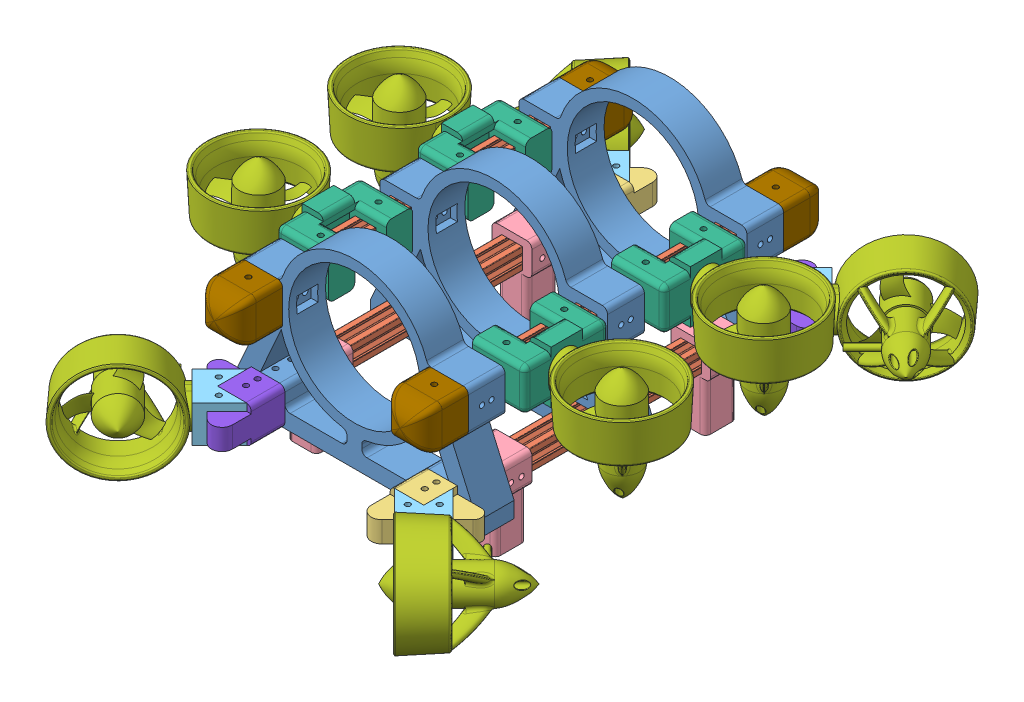
SolidWorks assembly aracson, configuration Varsayılan. Lengths in mm.
Overall size (470.39 214.66 570.15).
37 component instances, 10 part files, 72 mates.
Components (placement in the parent):
- tup30cmbirlesik-1: tup30cmbirlesik [Varsayılan] at (-12.712 13.1831 -30.3728) size (234 173.21 358.25)
  - auv_on-1: auv_on [Varsayılan] at (-0.4985 6.4776 216.5) size (234 172.66 35)
  - auvtup30cm-1: auvtup30cm [Default] at (13.0956 8.6338 230.5) x (0.999767 -0.021578 0) z (0 0 1) size (143.05 134.03 358.25) (hidden)
  - auv_on-2: auv_on [Varsayılan] at (-0.4985 6.4776 349) size (234 172.66 35)
  - auv_on-3: auv_on [Varsayılan] at (-0.4985 6.4776 481.5) size (234 172.66 35)
- sigma_20x20x1000-1: sigma_20x20x1000 [Varsayılan] at (71.7895 -62.5006 161.1272) x (0 0 1) z (-1 0 0) size (350 20 20)
- sigma_20x20x1000-2: sigma_20x20x1000 [Varsayılan] at (75.1683 19.479 161.1272) x (0 0 1) z (-1 0 0) size (350 20 20)
- sigma_20x20x1000-3: sigma_20x20x1000 [Varsayılan] at (-98.3505 -62.5006 161.1272) x (0 0 1) z (-1 0 0) size (350 20 20)
- sigma_20x20x1000-4: sigma_20x20x1000 [Varsayılan] at (-101.5893 19.479 161.1272) x (0 0 1) z (-1 0 0) size (350 20 20)
- motortutucuon - Copy (2)-1: motortutucuon - Copy (2) [Varsayılan] at (77.9913 -52.5006 504.2544) x (-1 0 0) z (0 -1 0) size (62.69 59.86 35)
- motortutucuon - Copy (2)-2: motortutucuon - Copy (2) [Varsayılan] at (-104.5523 -52.5006 168) x (1 0 0) z (0 -1 0) size (62.69 59.86 35)
- ayak-1: ayak [Varsayılan] at (-108.3505 -72.5006 421.1272) size (38 77 30)
- ayak-2: ayak [Varsayılan] at (-108.3505 -72.5006 221.1272) size (38 77 30)
- ayak-3: ayak [Varsayılan] at (61.7895 -72.5006 221.1272) size (38 77 30)
- ayak-4: ayak [Varsayılan] at (61.7895 -72.5006 421.1272) size (38 77 30)
- motortutucuarka-1: motortutucuarka [Varsayılan] at (107.3992 -77.5006 512.737) x (-0.707107 0 0.707107) z (-0.707107 0 -0.707107) size (39.6 35 36.98)
- motortutucuarka-2: motortutucuarka [Varsayılan] at (-105.9602 -77.5006 540.73) x (-0.707107 0 -0.707107) z (0.707107 0 -0.707107) size (39.6 35 36.98)
- motortutucuarka-3: motortutucuarka [Varsayılan] at (-133.9602 -77.5006 159.5175) x (0.707107 0 -0.707107) z (0.707107 0 0.707107) size (39.6 35 36.98)
- motortutucuarka-4: motortutucuarka [Varsayılan] at (79.3992 -77.5006 131.5245) x (0.707107 0 0.707107) z (-0.707107 0 0.707107) size (39.6 35 36.98)
- motorusttutucu-1: motorusttutucu [Varsayılan] at (55.1683 -0.521 362.3772) size (50 50 80)
- motorusttutucu-2: motorusttutucu [Varsayılan] at (55.1683 -0.521 229.8772) size (50 50 80)
- motorusttutucu-3: motorusttutucu [Varsayılan] at (-81.5893 39.479 229.8772) x (-1 0 0) z (0 0 1) size (50 50 80)
- motorusttutucu-4: motorusttutucu [Varsayılan] at (-81.5893 39.479 362.3772) x (-1 0 0) z (0 0 1) size (50 50 80)
- g350-ts-9: g350-ts [Default] at (104.9683 19.0095 404.8798) x (0 0.999962 0.008727) z (-1 0 0) size (107.98 96.84 103.47)
- g350-ts-10: g350-ts [Default] at (104.9683 19.4058 269.9346) x (0 0.999962 0.008727) z (-1 0 0) size (107.98 96.84 103.47)
- g350-ts-11: g350-ts [Default] at (-131.3893 18.7895 404.1961) x (0 0.999962 -0.008727) z (1 0 0) size (107.98 96.84 103.47)
- g350-ts-12: g350-ts [Default] at (-131.3893 20.0575 270.1899) x (0 0.999962 -0.008727) z (1 0 0) size (107.98 96.84 103.47)
- g350-ts-13: g350-ts [Default] at (92.9686 -63.0361 526.8847) x (-0.707107 0 0.707107) z (-0.707107 0 -0.707107) size (107.98 96.84 103.47)
- g350-ts-16: g350-ts [Default] at (-119.884 -61.7811 526.5234) x (0.707093 -0.006198 0.707093) z (0.707107 0 -0.707107) size (107.98 96.84 103.47)
- g350-ts-17: g350-ts [Default] at (93.3561 -66.3319 145.7642) x (-0.70708 0.008727 -0.70708) z (-0.707107 0 0.707107) size (107.98 96.84 103.47)
- g350-ts-18: g350-ts [Default] at (-119.9397 -63.3274 145.7798) x (0.707107 0 -0.707107) z (0.707107 0 0.707107) size (107.98 96.84 103.47)
- motortutucuon-1: motortutucuon [Varsayılan] at (-104.5523 -72.5006 504.2544) x (1 0 0) z (0 1 0) size (62.69 59.86 35)
- motortutucuon-2: motortutucuon [Varsayılan] at (77.9913 -72.5006 168) x (-1 0 0) z (0 1 0) size (62.69 59.86 35)
- kapak-1: kapak [Varsayılan] at (-111.5893 9.479 486.1272) size (40 40 45)
- kapak-2: kapak [Varsayılan] at (65.1683 9.479 486.1272) size (40 40 45)
- kapak-3: kapak [Varsayılan] at (-91.5893 9.479 186.1272) x (-1 0 0) z (0 0 -1) size (40 40 45)
- kapak-4: kapak [Varsayılan] at (85.1683 9.479 186.1272) x (-1 0 0) z (0 0 -1) size (40 40 45)
Mates (geometry in assembly coordinates):
- Coincident1: coincident anti-aligned: plane of tup30cmbirlesik-1/auv_on-2 through (-13.2105 -52.5006 353.6272) normal (0 -1 0); plane of sigma_20x20x1000-1 through (62.2895 -52.5006 511.1272) normal (0 1 0)
- Coincident2: coincident anti-aligned: plane of tup30cmbirlesik-1/auv_on-3 through (61.7895 19.6607 486.1272) normal (1 0 0); plane of sigma_20x20x1000-1 through (61.7895 -57.8506 511.1272) normal (-1 0 0)
- Coincident3: coincident anti-aligned: plane of tup30cmbirlesik-1/auv_on-3 through (-13.2105 29.479 486.1272) normal (0 -1 0); plane of sigma_20x20x1000-2 through (65.6683 29.479 511.1272) normal (0 1 0)
- Coincident4: coincident: plane of tup30cmbirlesik-1/auv_on-3 through (65.1683 19.6607 486.1272) normal (1 0 0); line of sigma_20x20x1000-2 through (65.1683 14.829 511.1272) axis (0 0 -1)
- Coincident5: coincident anti-aligned: plane of tup30cmbirlesik-1/auv_on-3 through (-111.5893 19.6607 486.1272) normal (1 0 0); plane of sigma_20x20x1000-4 through (-111.5893 24.129 511.1272) normal (-1 0 0)
- Coincident6: coincident anti-aligned: plane of tup30cmbirlesik-1/auv_on-3 through (-13.2105 29.479 486.1272) normal (0 -1 0); plane of sigma_20x20x1000-4 through (-111.0893 29.479 511.1272) normal (0 1 0)
- Coincident7: coincident anti-aligned: plane of tup30cmbirlesik-1/auv_on-3 through (-13.2105 -72.5006 486.1272) normal (0 1 0); plane of sigma_20x20x1000-3 through (-103.0005 -72.5006 511.1272) normal (0 -1 0)
- Coincident8: coincident anti-aligned: plane of tup30cmbirlesik-1/auv_on-3 through (-108.3505 19.6607 486.1272) normal (1 0 0); plane of sigma_20x20x1000-3 through (-108.3505 -72.0006 511.1272) normal (-1 0 0)
- Coincident11: coincident anti-aligned: plane of sigma_20x20x1000-1 through (81.7895 -67.1506 511.1272) normal (1 0 0); plane of motortutucuon - Copy (2)-1 through (81.7895 -72.5006 504.2544) normal (-1 0 0)
- Coincident12: coincident anti-aligned: plane of sigma_20x20x1000-1 through (81.2895 -72.5006 511.1272) normal (0 -1 0); plane of motortutucuon - Copy (2)-1 through (77.9913 -72.5006 504.2544) normal (0 1 0)
- Width1: width anti-aligned: plane of sigma_20x20x1000-1 through (64.9324 -57.3506 511.1272) normal (0 0 1); plane of sigma_20x20x1000-1 through (64.9324 -57.3506 161.1272) normal (0 0 -1); plane of tup30cmbirlesik-1/auv_on-1 through (-13.2105 19.6607 186.1272) normal (0 0 -1); plane of tup30cmbirlesik-1/auv_on-3 through (-13.2105 19.6607 486.1272) normal (0 0 1)
- Width2: width anti-aligned: plane of sigma_20x20x1000-2 through (68.3112 24.629 161.1272) normal (0 0 -1); plane of sigma_20x20x1000-2 through (68.3112 24.629 511.1272) normal (0 0 1); plane of tup30cmbirlesik-1/auv_on-3 through (-13.2105 19.6607 486.1272) normal (0 0 1); plane of tup30cmbirlesik-1/auv_on-1 through (-13.2105 19.6607 186.1272) normal (0 0 -1)
- Width3: width anti-aligned: plane of sigma_20x20x1000-4 through (-108.4464 24.629 511.1272) normal (0 0 1); plane of sigma_20x20x1000-4 through (-108.4464 24.629 161.1272) normal (0 0 -1); plane of tup30cmbirlesik-1/auv_on-1 through (-13.2105 19.6607 186.1272) normal (0 0 -1); plane of tup30cmbirlesik-1/auv_on-3 through (-13.2105 19.6607 486.1272) normal (0 0 1)
- Width4: width anti-aligned: plane of sigma_20x20x1000-3 through (-105.2076 -57.3506 511.1272) normal (0 0 1); plane of sigma_20x20x1000-3 through (-105.2076 -57.3506 161.1272) normal (0 0 -1); plane of tup30cmbirlesik-1/auv_on-1 through (-13.2105 19.6607 186.1272) normal (0 0 -1); plane of tup30cmbirlesik-1/auv_on-3 through (-13.2105 19.6607 486.1272) normal (0 0 1)
- Coincident13: coincident anti-aligned: line of sigma_20x20x1000-1 through (61.7895 -53.0006 511.1272) axis (0 -1 0); line of motortutucuon - Copy (2)-1 through (61.7895 -72.5006 511.1272) axis (0 1 0)
- Coincident17: coincident aligned: line of sigma_20x20x1000-3 through (-88.3505 -57.8506 161.1272) axis (0 1 0); line of motortutucuon - Copy (2)-2 through (-88.3505 -72.5006 161.1272) axis (0 1 0)
- Coincident18: coincident aligned: line of sigma_20x20x1000-3 through (-107.8505 -72.5006 161.1272) axis (1 0 0); line of motortutucuon - Copy (2)-2 through (-108.3505 -72.5006 161.1272) axis (1 0 0)
- Coincident23: coincident anti-aligned: plane of sigma_20x20x1000-3 through (-103.0005 -72.5006 511.1272) normal (0 -1 0); plane of ayak-2 through (-108.3505 -72.5006 251.1272) normal (0 1 0)
- Coincident24: coincident: point of tup30cmbirlesik-1/auv_on-1; unknown of ayak-2
- Coincident25: coincident anti-aligned: plane of sigma_20x20x1000-3 through (-108.3505 -72.0006 511.1272) normal (-1 0 0); plane of ayak-1 through (-108.3505 -72.5006 451.1272) normal (1 0 0)
- Coincident26: coincident: unknown of tup30cmbirlesik-1/auv_on-3; unknown of ayak-1
- Coincident27: coincident anti-aligned: plane of sigma_20x20x1000-3 through (-103.0005 -72.5006 511.1272) normal (0 -1 0); plane of ayak-1 through (-108.3505 -72.5006 451.1272) normal (0 1 0)
- Coincident28: coincident anti-aligned: plane of sigma_20x20x1000-3 through (-108.3505 -72.0006 511.1272) normal (-1 0 0); plane of ayak-2 through (-108.3505 -72.5006 251.1272) normal (1 0 0)
- Coincident29: coincident anti-aligned: plane of sigma_20x20x1000-1 through (81.7895 -67.1506 511.1272) normal (1 0 0); plane of ayak-4 through (81.7895 -72.5006 451.1272) normal (-1 0 0)
- Coincident30: coincident: unknown of tup30cmbirlesik-1/auv_on-3; unknown of ayak-4
- Coincident31: coincident anti-aligned: plane of sigma_20x20x1000-1 through (62.2895 -52.5006 511.1272) normal (0 1 0); plane of ayak-4 through (61.7895 -52.5006 451.1272) normal (0 -1 0)
- Coincident32: coincident anti-aligned: plane of sigma_20x20x1000-1 through (81.7895 -67.1506 511.1272) normal (1 0 0); plane of ayak-3 through (81.7895 -72.5006 251.1272) normal (-1 0 0)
- Coincident33: coincident: unknown of tup30cmbirlesik-1/auv_on-1; unknown of ayak-3
- Coincident34: coincident anti-aligned: plane of sigma_20x20x1000-1 through (76.4395 -52.5006 511.1272) normal (0 1 0); plane of ayak-3 through (61.7895 -52.5006 251.1272) normal (0 -1 0)
- Coincident36: coincident anti-aligned: line of motortutucuon - Copy (2)-1 through (57.7895 -45.5006 518.1272) axis (1 0 0); line of motortutucuarka-1 through (84.7895 -45.5006 518.1272) axis (-1 0 0)
- Coincident37: coincident anti-aligned: line of motortutucuon - Copy (2)-1 through (84.7895 -45.5006 518.1272) axis (0 0 -1); line of motortutucuarka-1 through (84.7895 -45.5006 490.1272) axis (0 0 1)
- Coincident45: coincident anti-aligned: line of motortutucuon - Copy (2)-2 through (-84.3505 -45.5006 154.1272) axis (-1 0 0); line of motortutucuarka-3 through (-111.3505 -45.5006 154.1272) axis (1 0 0)
- Coincident46: coincident anti-aligned: line of motortutucuon - Copy (2)-2 through (-111.3505 -45.5006 154.1272) axis (0 0 1); line of motortutucuarka-3 through (-111.3505 -45.5006 182.1272) axis (0 0 -1)
- Coincident47: coincident anti-aligned: plane of sigma_20x20x1000-2 through (79.8183 29.479 511.1272) normal (0 1 0); plane of motorusttutucu-1 through (65.1683 29.479 387.3772) normal (0 -1 0)
- Coincident48: coincident anti-aligned: plane of sigma_20x20x1000-2 through (65.1683 24.129 511.1272) normal (-1 0 0); plane of motorusttutucu-1 through (65.1683 9.479 387.3772) normal (1 0 0)
- Width5: width aligned: plane of tup30cmbirlesik-1/auv_on-3 through (-13.2105 19.6607 451.1272) normal (0 0 -1); plane of tup30cmbirlesik-1/auv_on-2 through (-13.2105 19.6607 353.6272) normal (0 0 1); plane of motorusttutucu-1 through (55.1683 -0.521 362.3772) normal (0 0 -1); plane of motorusttutucu-1 through (55.1683 -0.521 442.3772) normal (0 0 1)
- Coincident49: coincident anti-aligned: plane of sigma_20x20x1000-2 through (85.1683 28.979 511.1272) normal (1 0 0); plane of motorusttutucu-2 through (85.1683 9.479 254.8772) normal (-1 0 0)
- Coincident50: coincident anti-aligned: plane of sigma_20x20x1000-2 through (65.6683 29.479 511.1272) normal (0 1 0); plane of motorusttutucu-2 through (65.1683 29.479 254.8772) normal (0 -1 0)
- Width6: width anti-aligned: plane of tup30cmbirlesik-1/auv_on-2 through (-13.2105 19.6607 318.6272) normal (0 0 -1); plane of tup30cmbirlesik-1/auv_on-1 through (-13.2105 19.6607 221.1272) normal (0 0 1); plane of motorusttutucu-2 through (55.1683 -0.521 309.8772) normal (0 0 1); plane of motorusttutucu-2 through (55.1683 -0.521 229.8772) normal (0 0 -1)
- Coincident51: coincident anti-aligned: plane of sigma_20x20x1000-4 through (-111.0893 29.479 511.1272) normal (0 1 0); plane of motorusttutucu-4 through (-91.5893 29.479 387.3772) normal (0 -1 0)
- Coincident52: coincident anti-aligned: plane of sigma_20x20x1000-4 through (-91.5893 28.979 511.1272) normal (1 0 0); plane of motorusttutucu-4 through (-91.5893 29.479 387.3772) normal (-1 0 0)
- Width9: width anti-aligned: plane of motorusttutucu-4 through (-81.5893 39.479 442.3772) normal (0 0 1); plane of motorusttutucu-4 through (-81.5893 39.479 362.3772) normal (0 0 -1); plane of tup30cmbirlesik-1/auv_on-2 through (-13.2105 19.6607 318.6272) normal (0 0 -1); plane of tup30cmbirlesik-1/auv_on-3 through (-13.2105 19.6607 486.1272) normal (0 0 1)
- Coincident55: coincident anti-aligned: plane of sigma_20x20x1000-4 through (-106.2393 9.479 511.1272) normal (0 -1 0); plane of motorusttutucu-3 through (-91.5893 9.479 309.8772) normal (0 1 0)
- Coincident56: coincident anti-aligned: plane of sigma_20x20x1000-4 through (-91.5893 28.979 511.1272) normal (1 0 0); plane of motorusttutucu-3 through (-91.5893 29.479 309.8772) normal (-1 0 0)
- Width10: width anti-aligned: plane of motorusttutucu-3 through (-81.5893 39.479 309.8772) normal (0 0 1); plane of motorusttutucu-3 through (-81.5893 39.479 229.8772) normal (0 0 -1); plane of tup30cmbirlesik-1/auv_on-2 through (-13.2105 19.6607 318.6272) normal (0 0 -1); plane of tup30cmbirlesik-1/auv_on-1 through (-13.2105 19.6607 221.1272) normal (0 0 1)
- Coincident57: coincident anti-aligned: plane of motorusttutucu-1 through (105.1683 -0.521 387.3772) normal (1 0 0); plane of g350-ts-9 through (105.1683 23.1116 404.9156) normal (-1 0 0)
- Coincident58: coincident anti-aligned: plane of motorusttutucu-2 through (105.1683 -0.521 254.8772) normal (1 0 0); plane of g350-ts-10 through (105.1683 23.5079 269.9704) normal (-1 0 0)
- Coincident59: coincident anti-aligned: plane of motorusttutucu-4 through (-131.5893 39.479 387.3772) normal (-1 0 0); plane of g350-ts-11 through (-131.5893 22.8916 404.1603) normal (1 0 0)
- Coincident60: coincident anti-aligned: plane of motorusttutucu-3 through (-131.5893 39.479 254.8772) normal (-1 0 0); plane of g350-ts-12 through (-131.5893 24.1596 270.1541) normal (1 0 0)
- Coincident63: coincident: plane of motortutucuarka-2 through (-105.9602 -77.5006 540.73) normal (-0.707107 0 0.707107); plane of g350-ts-16 through (-117.1247 -61.8065 529.5655) normal (0.707107 0 -0.707107)
- Coincident64: coincident: plane of motortutucuarka-1 through (107.3992 -77.5006 512.737) normal (0.707107 0 0.707107); plane of g350-ts-13 through (90.2093 -63.0361 529.9269) normal (-0.707107 0 -0.707107)
- Coincident65: coincident: plane of motortutucuarka-4 through (79.3992 -77.5006 131.5245) normal (0.707107 0 -0.707107); plane of g350-ts-17 through (90.5969 -66.2961 142.7222) normal (-0.707107 0 0.707107)
- Coincident66: coincident: plane of motortutucuarka-3 through (-133.9602 -77.5006 159.5175) normal (-0.707107 0 -0.707107); plane of g350-ts-18 through (-117.1804 -63.3274 142.7377) normal (0.707107 0 0.707107)
- Coincident67: coincident anti-aligned: plane of sigma_20x20x1000-3 through (-103.0005 -72.5006 511.1272) normal (0 -1 0); plane of motortutucuon-1 through (-104.5523 -72.5006 504.2544) normal (0 1 0)
- Coincident68: coincident anti-aligned: plane of sigma_20x20x1000-3 through (-88.3505 -67.1506 511.1272) normal (1 0 0); plane of motortutucuon-1 through (-88.3505 -52.5006 504.2544) normal (-1 0 0)
- Coincident69: coincident: unknown of tup30cmbirlesik-1/auv_on-3; unknown of motortutucuon-1
- Coincident70: coincident aligned: circle of motortutucuarka-2; circle of motortutucuon-1
- Parallel1: parallel anti-aligned: line of motortutucuarka-2 through (-83.3505 -45.5006 518.1202) axis (-1 0 0); line of motortutucuon-1 through (-111.3505 -45.5006 518.1272) axis (1 0 0)
- Coincident73: coincident anti-aligned: plane of sigma_20x20x1000-1 through (61.7895 -57.8506 511.1272) normal (-1 0 0); plane of motortutucuon-2 through (61.7895 -52.5006 168) normal (1 0 0)
- Coincident74: coincident anti-aligned: plane of sigma_20x20x1000-1 through (81.2895 -72.5006 511.1272) normal (0 -1 0); plane of motortutucuon-2 through (77.9913 -72.5006 168) normal (0 1 0)
- Coincident75: coincident: line of tup30cmbirlesik-1/auv_on-1 through (81.7895 -52.5006 186.1272) axis (-1 0 0); unknown of motortutucuon-2
- Coincident76: coincident aligned: circle of motortutucuarka-4; circle of motortutucuon-2
- Parallel2: parallel anti-aligned: line of motortutucuarka-4 through (56.7895 -45.5006 154.1342) axis (1 0 0); line of motortutucuon-2 through (84.7895 -45.5006 154.1272) axis (-1 0 0)
- Coincident78: coincident anti-aligned: line of tup30cmbirlesik-1/auv_on-3 through (-116.5893 39.479 486.1272) axis (1 0 0); line of kapak-1 through (-86.5893 39.479 486.1272) axis (-1 0 0)
- Coincident79: coincident anti-aligned: line of tup30cmbirlesik-1/auv_on-3 through (-121.5893 4.479 486.1272) axis (0 1 0); line of kapak-1 through (-121.5893 34.479 486.1272) axis (0 -1 0)
- Coincident80: coincident aligned: line of tup30cmbirlesik-1/auv_on-3 through (90.1683 39.479 486.1272) axis (-1 0 0); line of kapak-2 through (90.1683 39.479 486.1272) axis (-1 0 0)
- Coincident81: coincident aligned: line of tup30cmbirlesik-1/auv_on-3 through (95.1683 4.479 486.1272) axis (0 1 0); line of kapak-2 through (95.1683 4.479 486.1272) axis (0 1 0)
- Coincident82: coincident aligned: line of tup30cmbirlesik-1/auv_on-1 through (-116.5893 39.479 186.1272) axis (1 0 0); line of kapak-3 through (-116.5893 39.479 186.1272) axis (1 0 0)
- Coincident83: coincident: plane of tup30cmbirlesik-1/auv_on-1 through (-121.5893 19.6607 221.1272) normal (-1 0 0); line of kapak-3 through (-121.5893 4.479 186.1272) axis (0 1 0)
- Coincident84: coincident aligned: line of tup30cmbirlesik-1/auv_on-1 through (-121.5893 4.479 186.1272) axis (0 1 0); line of kapak-3 through (-121.5893 4.479 186.1272) axis (0 1 0)
- Coincident85: coincident anti-aligned: line of tup30cmbirlesik-1/auv_on-1 through (90.1683 39.479 186.1272) axis (-1 0 0); line of kapak-4 through (60.1683 39.479 186.1272) axis (1 0 0)
- Coincident86: coincident anti-aligned: line of tup30cmbirlesik-1/auv_on-1 through (95.1683 4.479 186.1272) axis (0 1 0); line of kapak-4 through (95.1683 34.479 186.1272) axis (0 -1 0)
